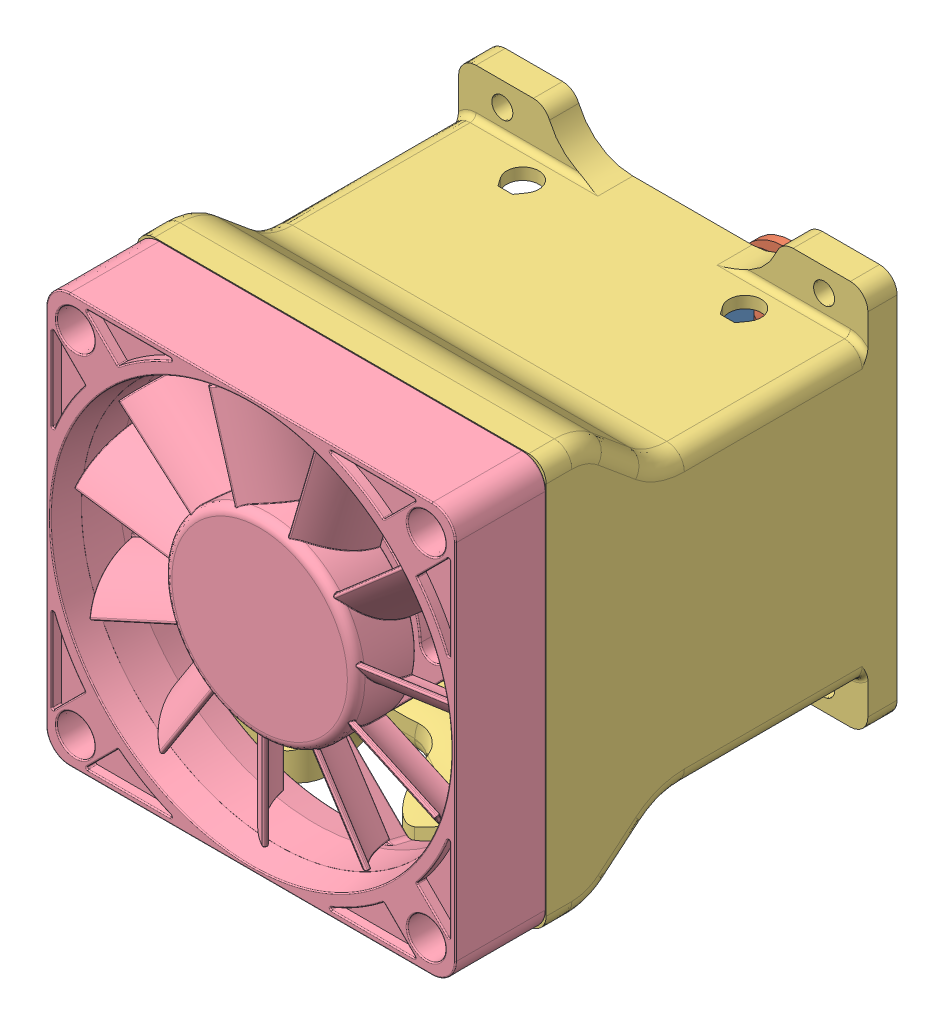
SolidWorks assembly Laser_Module, configuration Predeterminado. Lengths in mm.
Overall size (70 70 94.5).
4 component instances, 4 part files, 11 mates.
Components (placement in the parent):
- Laser_Holder_Heatsink-1: Laser_Holder_Heatsink [Predeterminado] at origin size (48 44 16)
- Laser_housing-1: Laser_housing [Predeterminado] at (0 27 -27) x (1 0 0) z (0 -1 0) size (16 52 16)
- Laser_cover-1: Laser_cover [Predeterminado] at (0 23 50) x (-1 0 0) z (0 0 -1) size (70 70 62.67)
- PC Fan-1: PC Fan [Default] at (0 23 50) x (1 0 0) z (0 -1 0) size (70 15.5 70)
Mates (geometry in assembly coordinates):
- Concéntrica1: concentric anti-aligned: cylinder of Laser_Holder_Heatsink-1 through (0 27 8) axis (0 0 -1) radius 8; cylinder of Laser_housing-1 through (0 27 41.764) axis (0 0 1) radius 8
- Distancia1: distance = 15 mm aligned: plane of Laser_housing-1 through (0 27 23) normal (0 0 1); plane of Laser_Holder_Heatsink-1 through (0 27 8) normal (0 0 1)
- Coincidente2: coincident anti-aligned: plane of Laser_Holder_Heatsink-1 through (-24 0 8) normal (0 -1 0); plane of Laser_cover-1 through (-33 0 -10) normal (0 1 0)
- Concéntrica2: concentric aligned: cylinder of Laser_Holder_Heatsink-1 through (-19 0 0) axis (0 1 0) radius 2.5; cylinder of Laser_cover-1 through (-19 -10 0) axis (0 1 0) radius 2.75
- Concéntrica5: concentric aligned: cylinder of Laser_Holder_Heatsink-1 through (19 0 0) axis (0 1 0) radius 2.5; cylinder of Laser_cover-1 through (19 -10 0) axis (0 1 0) radius 2.75
- Coincidente3: coincident anti-aligned: plane of Laser_cover-1 through (0 23 50) normal (0 0 1); plane of PC Fan-1 through (35 -12 50) normal (0 0 -1)
- Distancia2: distance = 10 mm aligned: plane of Laser_cover-1 through (35 -2 -10) normal (0 -1 0); plane of PC Fan-1 through (-35 -12 65.5) normal (0 -1 0)
- Coincidente5: coincident aligned: plane of PC Fan-1; plane of assembly through (0 0 0) normal (1 0 0)
- Coincidente6: coincident aligned: plane of Laser_Holder_Heatsink-1 through (0 0 0) normal (0 0 1); plane of assembly through (0 0 0) normal (0 0 1)
- Coincidente7: coincident aligned: plane of Laser_Holder_Heatsink-1 through (0 0 0) normal (0 1 0); plane of assembly through (0 0 0) normal (0 1 0)
- Coincidente8: coincident: point of Laser_Holder_Heatsink-1; plane of assembly
